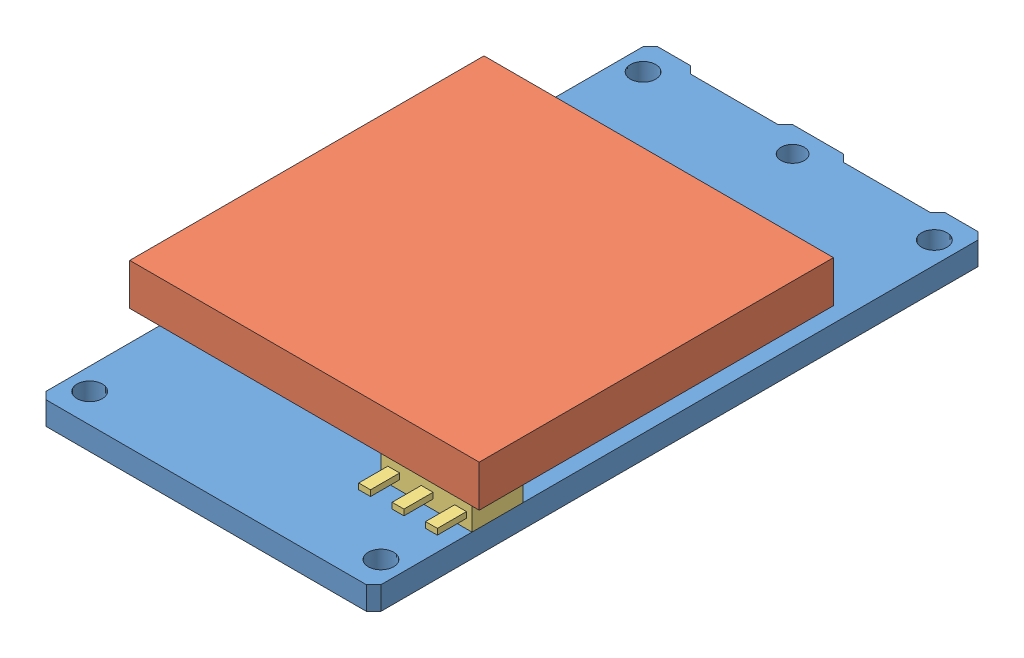
SolidWorks assembly IRS2_DC.revB2, configuration Default. Lengths in mm.
Overall size (32 10.55 42).
4 component instances, 4 part files, 7 mates.
Components (placement in the parent):
- IRS2_DC.revB2-1: IRS2_DC.revB2 [Default] at origin size (23 1.59 42)
- IRS2_DC.revB2.heatsink-2: IRS2_DC.revB2.heatsink [Default] at origin size (32 7.55 20.75)
- SOT-223-1: SOT-223 [Default] at (16.75 1.5875 -6.7541) size (6.25 1.55 7.25)
- 80-pin-connectors-1: 80-pin-connectors [Default] x (-1 0 0) z (0 -1 0) size (22.38 29 3)
Mates (geometry in assembly coordinates):
- Coincident1: coincident anti-aligned: plane of IRS2_DC.revB2-1 through (23 1.5875 0) normal (0 1 0); plane of IRS2_DC.revB2.heatsink-2 through (10.75 1.5875 -26.25) normal (0 -1 0)
- Coincident6: coincident anti-aligned: plane of IRS2_DC.revB2-1 through (23 1.5875 0) normal (0 1 0); plane of SOT-223-1 through (16.75 1.5875 -6.7541) normal (0 -1 0)
- Coincident7: coincident aligned: plane of IRS2_DC.revB2-1 through (23 1.5875 -0.5) normal (1 0 0); plane of SOT-223-1 through (23 3.1425 -6.7541) normal (1 0 0)
- InPlace1: in place: plane of ? through (23 0 0) normal (0 -1 0); plane of 80-pin-connectors-1 through (0 0 0) normal (0 -1 0); moOrthogonalPlaneRef_w of ? through (23 0 0) normal (0 -1 0); unknown of 80-pin-connectors-1; plane of ? through (23 0 0) normal (0 -1 0); line of 80-pin-connectors-1 through (55 -55 0) axis (0 0 -1); plane of ? through (23 0 0) normal (0 -1 0); unknown of 80-pin-connectors-1
- Coincident8: coincident aligned: plane of IRS2_DC.revB2-1; plane of 80-pin-connectors-1
- Coincident9: coincident aligned: moOrthogonalPlaneRef_w of IRS2_DC.revB2-1 through (0 0 0) normal (0 0 -1); plane of 80-pin-connectors-1
- Coincident10: coincident anti-aligned: moOrthogonalPlaneRef_w of IRS2_DC.revB2-1 through (0 0 0) normal (1 0 0); plane of 80-pin-connectors-1
